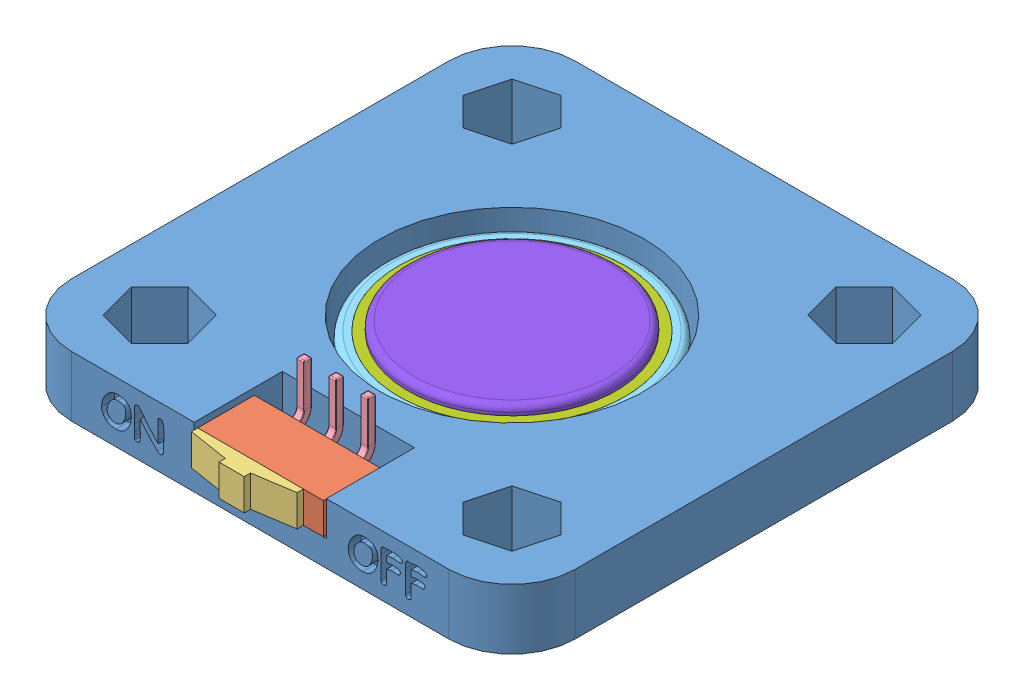
SolidWorks assembly kostka, configuration Výchozí. Lengths in mm.
Overall size (40 7.65 41.5).
12 component instances, 8 part files, 3 mates.
Components (placement in the parent):
- krabca-1: krabca [Výchozí] at origin size (40 4.8 40)
- vypinac-1: vypinac [Výchozí] at (0.025 3.3 15) size (10 5.6 7.8)
  - zaklad-1: zaklad [Výchozí] at origin size (10 2.5 5)
  - cudlik-1: cudlik [Výchozí] at (-0.8 -1.25 5.75) x (-1 0 0) z (0 0 -1) size (8.4 2.5 1.5)
  - vyvod-3: vyvod [Výchozí] at (-2.54 4.255 -1) x (0 1 0) z (1 0 0) size (4.65 2.3 0.6)
  - vyvod-4: vyvod [Výchozí] at (0 4.255 -1) x (0 1 0) z (1 0 0) size (4.65 2.3 0.6)
  - vyvod-5: vyvod [Výchozí] at (2.54 4.255 -1) x (0 1 0) z (1 0 0) size (4.65 2.3 0.6)
- CR2032-1: CR2032 [Výchozí] at (0 1.2406 0) x (0.993524 0 0.113622) z (-0.113622 0 0.993524) size (24.84 3.3 24.84)
  - plus-1: plus [Výchozí] at origin size (20 2.46 20)
  - potisk-1: potisk [Výchozí] at (0 -0.1 0) size (13.99 0.2 13.19)
  - izolace-1: izolace [Výchozí] x (0.84483 0 -0.535035) z (0.535035 0 0.84483) size (18 1.46 18)
  - minus-1: minus [Výchozí] at origin size (16.5 0.74 16.5)
Mates (geometry in assembly coordinates):
- Sjednocená1: coincident anti-aligned: plane of krabca-1 through (5.25 2.05 13) normal (0 1 0); plane of vypinac-1/zaklad-1 through (5.025 2.05 20) normal (0 -1 0)
- Sjednocená2: coincident aligned: plane of krabca-1 through (20 4.8 20) normal (0 0 1); plane of vypinac-1/zaklad-1 through (0.025 3.3 20) normal (0 0 1)
- Soustředná1: concentric anti-aligned: cylinder of krabca-1 through (0 4.8 0) axis (0 -1 0) radius 10.5; cylinder of CR2032-1/plus-1 through (0 2.2406 0) axis (0 1 0) radius 10
